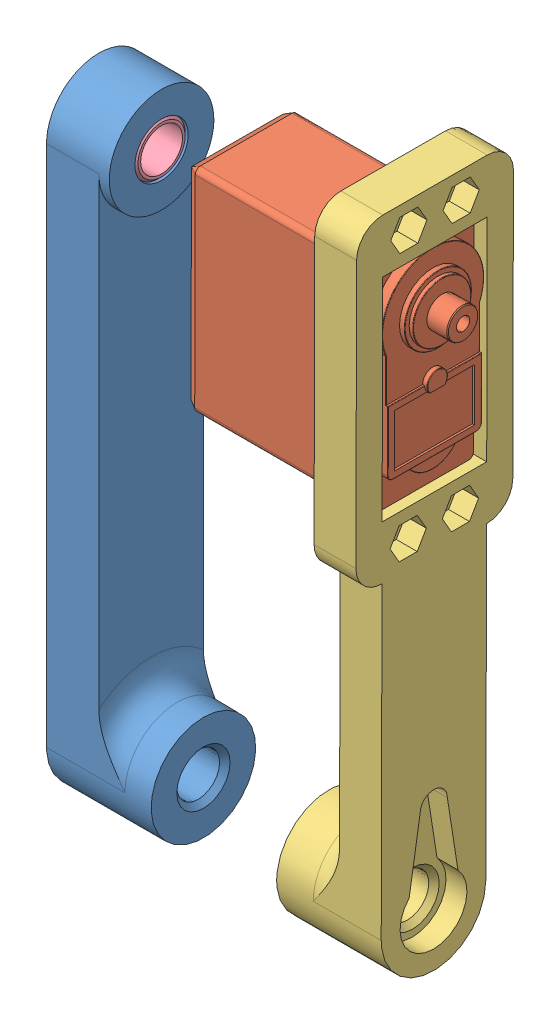
SolidWorks assembly AssemblyShoulder, configuration По умолчанию. Lengths in mm.
Overall size (69.65 130.07 30.32).
4 component instances, 4 part files, 6 mates.
Components (placement in the parent):
- Shoulder1-1: Shoulder1 [По умолчанию] at (-32 39.75 0) x (0 1 0) z (-1 0 0) size (120 20 20)
- MG995-1: MG995 [預設] at (21.46 108.9757 -9.6731) x (0 0.999997 -0.0025) z (0 -0.0025 -0.999997) size (54.5 43.19 19.5)
- Shoulder2-1: Shoulder2 [По умолчанию] at (32 39.7497 0) x (0 0.0025 0.999997) z (-1 0 0) size (30 130 20)
- sleeve-1: sleeve [По умолчанию] at (-20 139.75 0) x (0 0 1) z (-1 0 0) size (10 10 12)
Mates (geometry in assembly coordinates):
- Концентричный7: concentric aligned: cylinder of Shoulder1-1 through (-20 139.75 0) axis (-1 0 0) radius 5.1; cylinder of MG995-1 through (37.65 139.75 0) axis (-1 0 0) radius 2.925
- Совпадение7: coincident anti-aligned: plane of MG995-1 through (30 108.9757 -9.6731) normal (0 -0.999997 0.0025); plane of Shoulder2-1 through (24 108.9995 -0.1731) normal (0 0.999997 -0.0025)
- Совпадение8: coincident anti-aligned: plane of MG995-1 through (24 108.9985 -0.5481) normal (1 0 0); plane of Shoulder2-1 through (24 39.7497 0) normal (-1 0 0)
- Совпадение9: coincident anti-aligned: plane of MG995-1 through (30 109.0245 9.8268) normal (0 0.0025 0.999997); plane of Shoulder2-1 through (24 39.7747 10) normal (0 -0.0025 -0.999997)
- Концентричный29: concentric anti-aligned: cylinder of Shoulder1-1 through (-20 139.75 0) axis (-1 0 0) radius 5.1; cylinder of sleeve-1 through (-32 139.75 0) axis (1 0 0) radius 5
- Совпадение45: coincident aligned: plane of Shoulder1-1 through (-32 39.75 0) normal (-1 0 0); plane of sleeve-1 through (-32 139.75 0) normal (-1 0 0)
